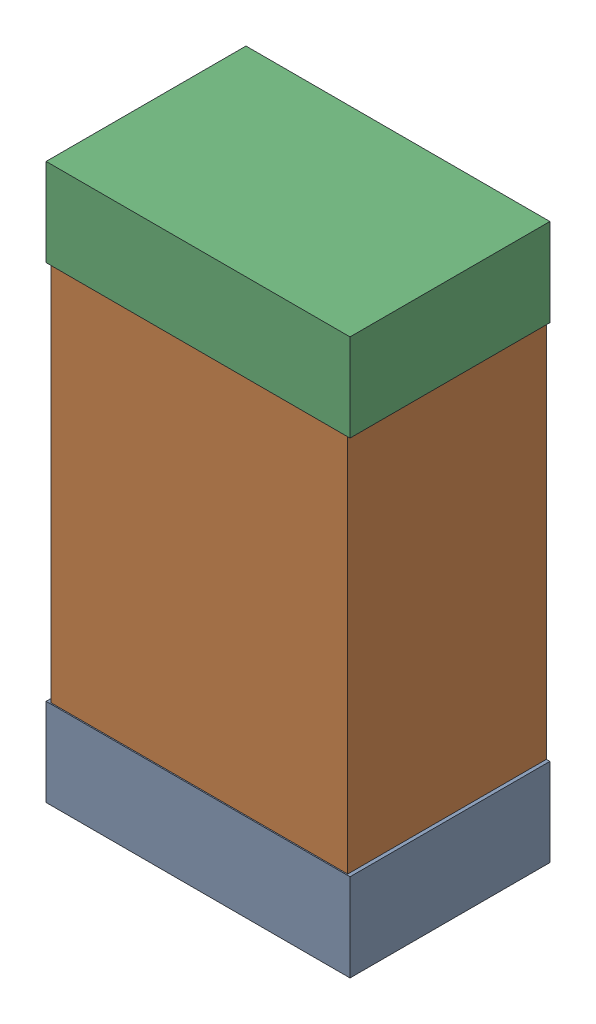
SolidWorks assembly C1Kanaloa_v2.0.0_Motor, configuration Default. Lengths in mm.
Overall size (1.3 2.38 0.85).
6 component instances, 2 part files, 0 mates.
Components (placement in the parent):
- 330415056-1: 330415056 [Default] at (81.28 119.65 0) size (1.3 0.38 0.85)
  - Extruded_2-1: Extruded_2 [Default] at origin size (1.3 0.38 0.85)
- 334787376-1: 334787376 [Default] at (81.28 120.65 0) size (1.27 2.2 0.85)
  - Extruded_16-1: Extruded_16 [Default] at origin size (1.27 2.2 0.85)
- 330415056-2: 330415056 [Default] at (81.28 121.65 0) size (1.3 0.38 0.85)
  - Extruded_2-1: Extruded_2 [Default] at origin size (1.3 0.38 0.85)
